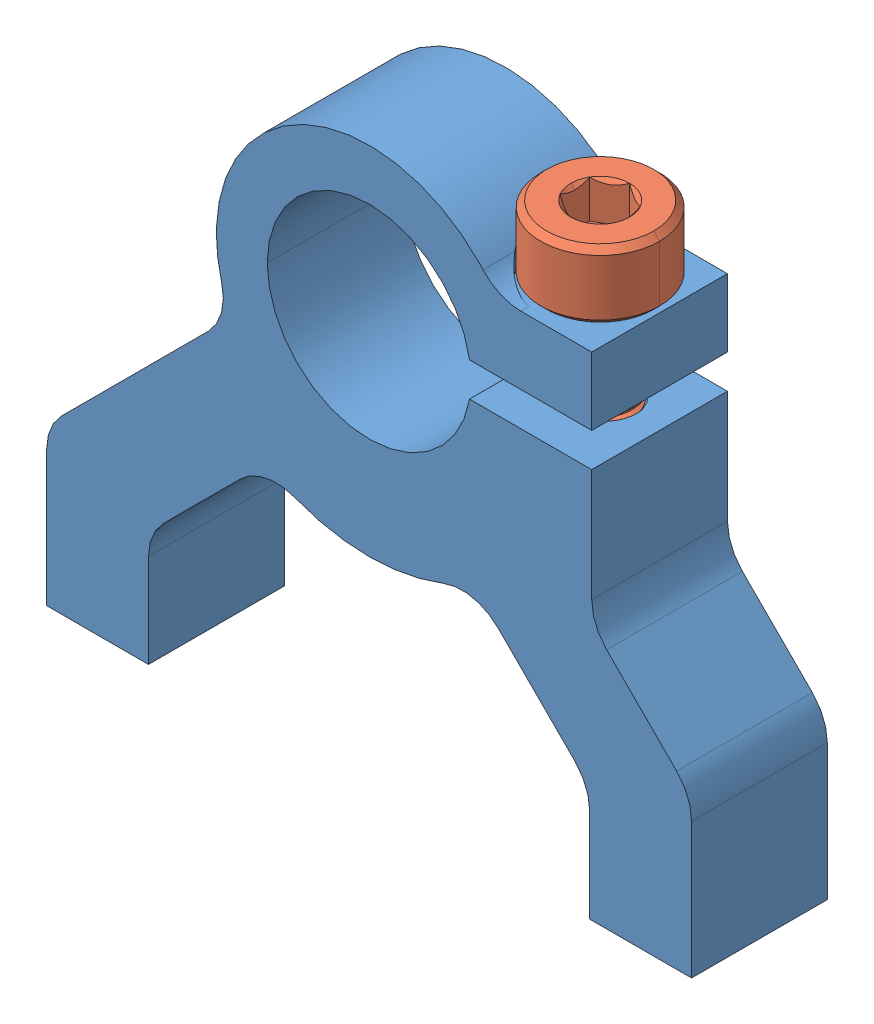
SolidWorks assembly 1-Side, 2-Post Clamping Mount (12mm Bore)1400-0032-0012, configuration Default. Lengths in mm.
Overall size (38 33.01 8).
2 component instances, 2 part files, 0 mates.
Components (placement in the parent):
- 1400-0032-0012.STEP-1: 1400-0032-0012.STEP [Default] at (-29.2242 38.3212 -9.4339) size (38 33 8)
- 2800-0004-0010_90128A207.STEP-1: 2800-0004-0010_90128A207.STEP [Default] at (-19.6082 33.3212 -5.4339) x (1 0 0) z (0 -1 0) size (7 7 14.01)
